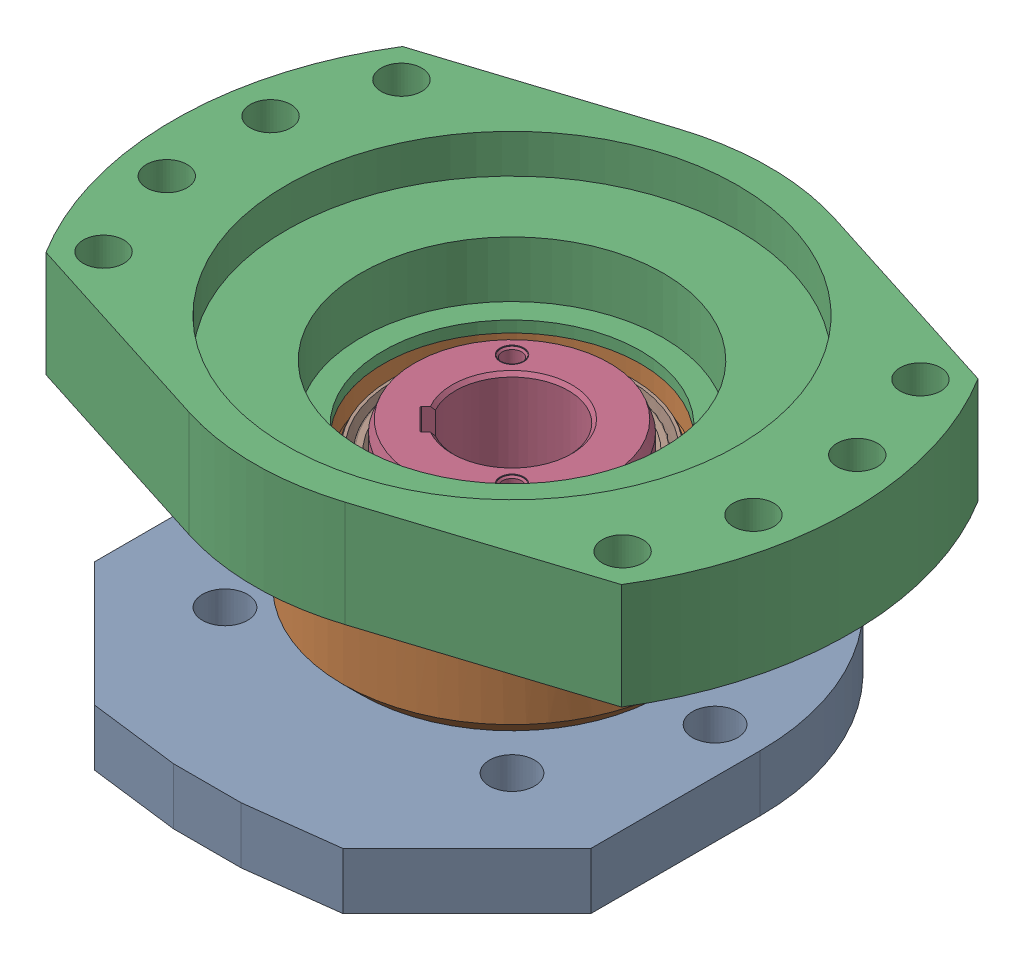
SolidWorks assembly g1_3_1_1_1_2, configuration 默认. Lengths in mm.
Overall size (300 165.8 249).
13 component instances, 8 part files, 0 mates.
Components (placement in the parent):
- g1_3_1_1_1_1_1-1: g1_3_1_1_1_1_1 [默认] at origin size (300 154 249)
  - g1_3_1_1_1_1-1_af0_1-1: g1_3_1_1_1_1-1_af0_1 [默认] at origin size (220 42 245)
  - g1_3_1_1_1_1-2_af0_1-1: g1_3_1_1_1_1-2_af0_1 [默认] at (0 50 0) size (150 65 150)
  - g1_3_1_1_1_1-3_af0_1-1: g1_3_1_1_1_1-3_af0_1 [默认] at (0 140 0) size (300 47 228)
- g1_3_1_1_1-2_1-1: g1_3_1_1_1-2_1 [默认] at (0 122.2 0) x (0.707107 0 0.707107) z (0.707107 0 -0.707107) size (90 126 90)
- g1_3_1_1_1-1_1-1: g1_3_1_1_1-1_1 [默认] at (0 77 0) x (0 1 0) z (0 0 1) size (20 110 110)
- b90x110x12_gb9877_1_1-1: b90x110x12_gb9877_1_1 [默认] at (0 66.9 0) size (108.6 17.9 108.6)
  - b90x110x12_gb9877_1_rubber_1-1: b90x110x12_gb9877_1_rubber_1 [默认] at origin size (108.6 12 108.6)
  - b90x110x12_gb9877_1_frame_1-1: b90x110x12_gb9877_1_frame_1 [默认] at (0 -2.4 0) x (-1 0 0) z (0 0 1) size (107.2 9.5 107.2)
- b90x110x12_gb9877_1_1-2: b90x110x12_gb9877_1_1 [默认] at (0 104.8 0) size (108.6 17.9 108.6)
  - b90x110x12_gb9877_1_rubber_1-1: b90x110x12_gb9877_1_rubber_1 [默认] at origin size (108.6 12 108.6)
  - b90x110x12_gb9877_1_frame_1-1: b90x110x12_gb9877_1_frame_1 [默认] at (0 -2.4 0) x (-1 0 0) z (0 0 1) size (107.2 9.5 107.2)
- 80_gb894_1_1-1: 80_gb894_1_1 [默认] at (-2.4 11.1 -38.1746) x (1 0 0) z (0 -1 0) size (85.83 90.87 2.5)
